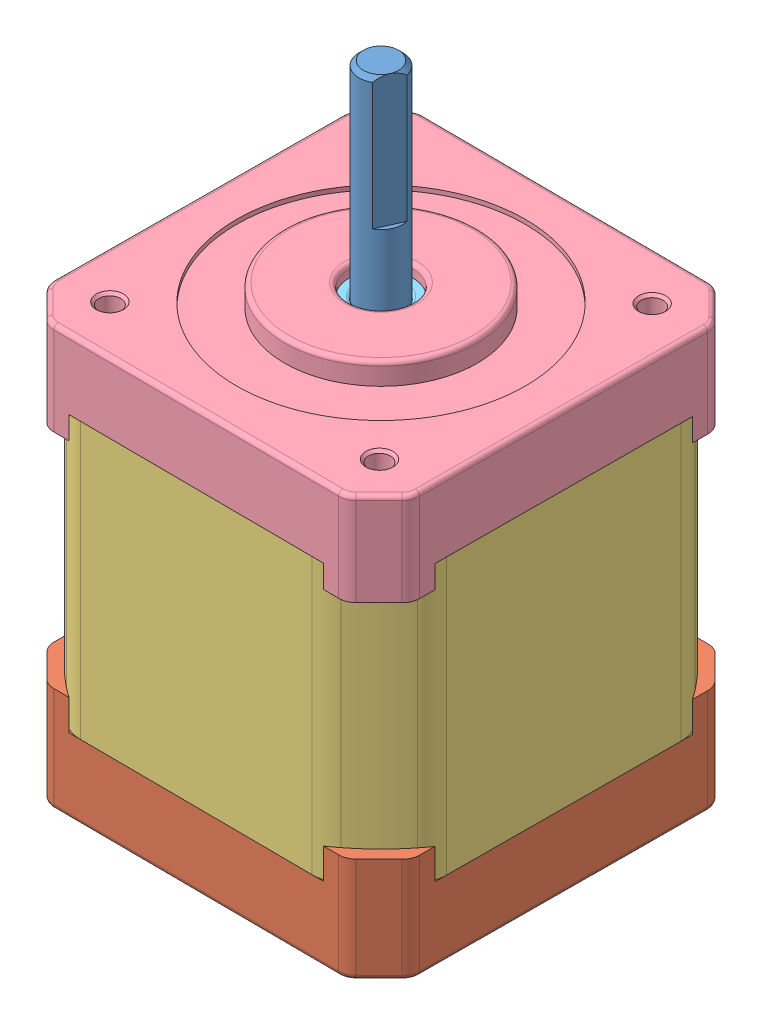
SolidWorks assembly 1704HS168A, configuration По умолчанию. Lengths in mm.
Overall size (42.24 72 42.24).
10 component instances, 6 part files, 16 mates.
Components (placement in the parent):
- nema17_shaft_1704HS168A-1: nema17_shaft_1704HS168A [По умолчанию] at (13.0746 21 -1.623) x (-0.412738 0 0.91085) z (-0.91085 0 -0.412738) size (5 72 5)
- nema17_bottom_1704HS168A-1: nema17_bottom_1704HS168A [По умолчанию] at (13.0746 21 -1.623) x (0.999984 0 0.005702) z (-0.005702 0 0.999984) size (42 12 42)
- nema17_middle_1704HS168A-1: nema17_middle_1704HS168A [По умолчанию] at (13.0746 29.5 -1.623) x (0.999984 0 0.005702) z (-0.005702 0 0.999984) size (42 31.5 42)
- nema17_top_1704HS168A-1: nema17_top_1704HS168A [По умолчанию] at (13.0746 61 -1.623) x (0.999984 0 0.005702) z (-0.005702 0 0.999984) size (42 12.6 42)
- radial ball bearing_68_din-1: radial ball bearing_68_din [DIN 625 - 625 - 8,SI,NC,8_68] at (13.0746 26 -1.623) x (0 -1 0) z (0 0 1) size (5 16 16)
- radial ball bearing_68_din-3: radial ball bearing_68_din [DIN 625 - 625 - 8,SI,NC,8_68] at (13.0746 67.1 -1.623) x (0 1 0) z (0 0 1) size (5 16 16)
- countersunk flat head cross recess screw_din-5: countersunk flat head cross recess screw_din [ISO 7046-1 - M3 x 30 - Z --- 30N] at (28.4859 21.6 13.9651) x (0 1 0) z (0.546944 0 -0.837169) size (30 5.5 5.5)
- countersunk flat head cross recess screw_din-7: countersunk flat head cross recess screw_din [ISO 7046-1 - M3 x 30 - Z --- 30N] at (28.6627 21.6 -17.0344) x (0 1 0) z (0.546944 0 -0.837169) size (30 5.5 5.5)
- countersunk flat head cross recess screw_din-6: countersunk flat head cross recess screw_din [ISO 7046-1 - M3 x 30 - Z --- 30N] at (-2.5136 21.6 13.7883) x (0 1 0) z (0.546944 0 -0.837169) size (30 5.5 5.5)
- countersunk flat head cross recess screw_din-8: countersunk flat head cross recess screw_din [ISO 7046-1 - M3 x 30 - Z --- 30N] at (-2.3368 21.6 -17.2112) x (0 1 0) z (0.546944 0 -0.837169) size (30 5.5 5.5)
Mates (geometry in assembly coordinates):
- Совпадение1: coincident anti-aligned: plane of nema17_bottom_1704HS168A-1 through (13.0746 23.5 -1.623) normal (0 1 0); plane of radial ball bearing_68_din-1 through (20.7746 23.5 -1.623) normal (0 -1 0)
- Концентричный1: concentric anti-aligned: cylinder of nema17_bottom_1704HS168A-1 through (13.0746 23.5 -1.623) axis (0 1 0) radius 8; cylinder of radial ball bearing_68_din-1 through (13.0746 46.6375 -1.623) axis (0 -1 0) radius 8
- Совпадение4: coincident anti-aligned: plane of nema17_top_1704HS168A-1 through (13.0746 69.6 -1.623) normal (0 -1 0); plane of radial ball bearing_68_din-3 through (5.3746 69.6 -1.623) normal (0 1 0)
- Концентричный6: concentric anti-aligned: cylinder of nema17_top_1704HS168A-1 through (13.0746 69.6 -1.623) axis (0 -1 0) radius 8; cylinder of radial ball bearing_68_din-3 through (13.0746 46.4625 -1.623) axis (0 1 0) radius 8
- Совпадение5: coincident aligned: cone of nema17_bottom_1704HS168A-1 through (28.4859 21 13.9651) axis (0 1 0); cone of countersunk flat head cross recess screw_din-5 through (28.4859 22 13.9651) axis (0 1 0)
- Совпадение6: coincident aligned: cone of nema17_bottom_1704HS168A-1 through (28.6627 21 -17.0344) axis (0 1 0); cone of countersunk flat head cross recess screw_din-7 through (28.6627 22 -17.0344) axis (0 1 0)
- Совпадение7: coincident aligned: cone of nema17_bottom_1704HS168A-1 through (-2.5136 21 13.7883) axis (0 1 0); cone of countersunk flat head cross recess screw_din-6 through (-2.5136 22 13.7883) axis (0 1 0)
- Совпадение8: coincident aligned: cone of nema17_bottom_1704HS168A-1 through (-2.3368 21 -17.2112) axis (0 1 0); cone of countersunk flat head cross recess screw_din-8 through (-2.3368 22 -17.2112) axis (0 1 0)
- Концентричный8: concentric aligned: cylinder of nema17_top_1704HS168A-1 through (13.0746 71 -1.623) axis (0 -1 0) radius 3.65; cylinder of nema17_shaft_1704HS168A-1 through (13.0746 93 -1.623) axis (0 -1 0) radius 2.5
- Расстояние1: distance = 22 mm aligned: plane of nema17_shaft_1704HS168A-1 through (13.0746 93 -1.623) normal (0 1 0); plane of nema17_top_1704HS168A-1 through (13.0746 71 -1.623) normal (0 1 0)
- Совпадение10: coincident anti-aligned: plane of nema17_top_1704HS168A-1 through (13.0746 61 -1.623) normal (0 -1 0); plane of nema17_middle_1704HS168A-1 through (13.0746 61 -1.623) normal (0 1 0)
- Концентричный10: concentric aligned: cylinder of nema17_top_1704HS168A-1 through (28.4859 69 13.9651) axis (0 -1 0) radius 1.25; cylinder of nema17_middle_1704HS168A-1 through (28.4859 61 13.9651) axis (0 -1 0) radius 1.25
- Концентричный11: concentric aligned: cylinder of nema17_top_1704HS168A-1 through (-2.3368 69 -17.2112) axis (0 -1 0) radius 1.25; cylinder of nema17_middle_1704HS168A-1 through (-2.3368 61 -17.2112) axis (0 -1 0) radius 1.25
- Концентричный12: concentric aligned: cylinder of nema17_bottom_1704HS168A-1 through (-2.5136 29.5 13.7883) axis (0 -1 0) radius 1.25; cylinder of nema17_top_1704HS168A-1 through (-2.5136 69 13.7883) axis (0 -1 0) radius 1.25
- Концентричный13: concentric aligned: cylinder of nema17_bottom_1704HS168A-1 through (28.6627 29.5 -17.0344) axis (0 -1 0) radius 1.25; cylinder of nema17_top_1704HS168A-1 through (28.6627 69 -17.0344) axis (0 -1 0) radius 1.25
- Совпадение11: coincident anti-aligned: plane of nema17_bottom_1704HS168A-1 through (13.0746 29.5 -1.623) normal (0 1 0); plane of nema17_middle_1704HS168A-1 through (13.0746 29.5 -1.623) normal (0 -1 0)
